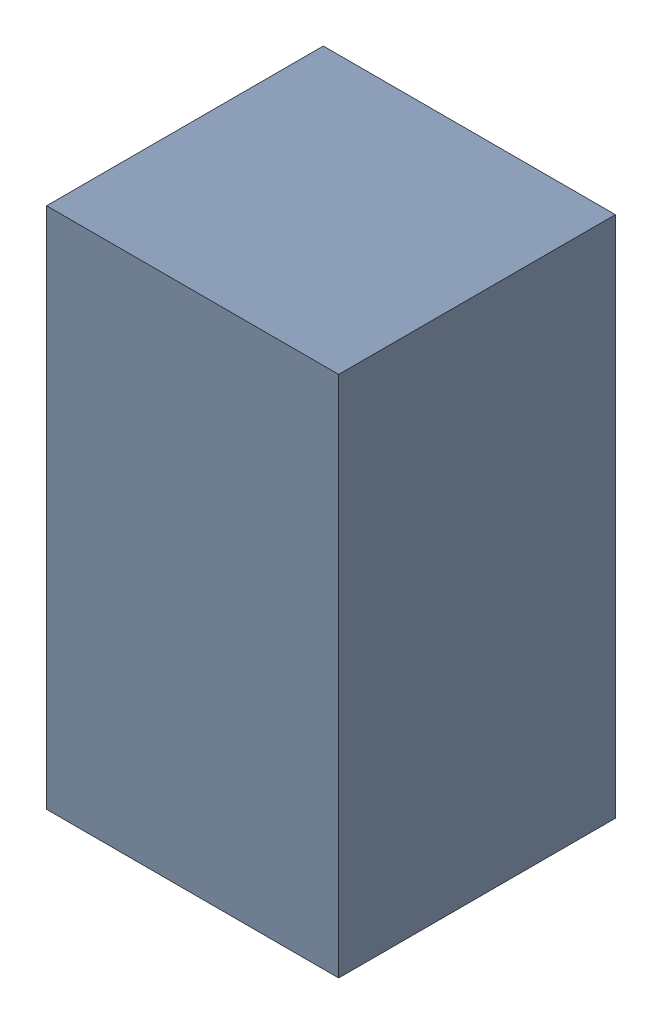
SolidWorks assembly R13, configuration Standard. Lengths in mm.
Overall size (0.95 1.7 0.9).
2 component instances, 1 part files, 0 mates.
Components (placement in the parent):
- 885541560-1: 885541560 [Standard] at (-20.25 0.5 0) size (0.95 1.7 0.9)
  - Extruded_16-1: Extruded_16 [Standard] at origin size (0.95 1.7 0.9)
